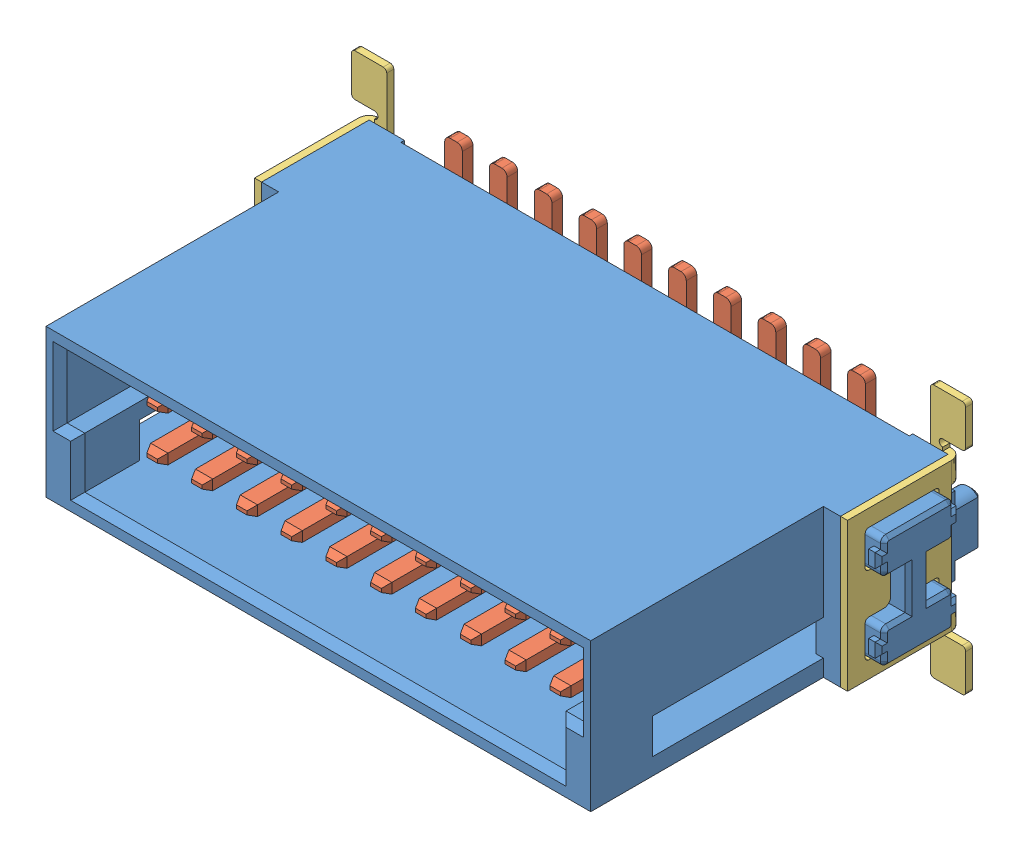
SolidWorks assembly m55-7022042_asm, configuration Default. Lengths in mm.
Overall size (17.78 7.2 10.6).
24 component instances, 3 part files, 0 mates.
Components (placement in the parent):
- m55-7022042_asm.stp-1: m55-7022042_asm.stp [Default] at origin size (17.78 7.2 10.6)
  - M55-70220_MOULD.stp-1: M55-70220_MOULD.stp [Default] at origin size (17.78 4.2 10.6)
  - M55-702_CONTACT.stp-1: M55-702_CONTACT.stp [Default] at (-5.715 -0.785 8.85) x (1 0 0) z (0 1 0) size (1.1 8.85 2.42)
  - M55-702_CONTACT.stp-2: M55-702_CONTACT.stp [Default] at (-4.445 -0.785 8.85) x (1 0 0) z (0 1 0) size (1.1 8.85 2.42)
  - M55-702_CONTACT.stp-3: M55-702_CONTACT.stp [Default] at (-3.175 -0.785 8.85) x (1 0 0) z (0 1 0) size (1.1 8.85 2.42)
  - M55-702_CONTACT.stp-4: M55-702_CONTACT.stp [Default] at (-1.905 -0.785 8.85) x (1 0 0) z (0 1 0) size (1.1 8.85 2.42)
  - M55-702_CONTACT.stp-5: M55-702_CONTACT.stp [Default] at (-0.635 -0.785 8.85) x (1 0 0) z (0 1 0) size (1.1 8.85 2.42)
  - M55-702_CONTACT.stp-6: M55-702_CONTACT.stp [Default] at (0.635 -0.785 8.85) x (1 0 0) z (0 1 0) size (1.1 8.85 2.42)
  - M55-702_CONTACT.stp-7: M55-702_CONTACT.stp [Default] at (1.905 -0.785 8.85) x (1 0 0) z (0 1 0) size (1.1 8.85 2.42)
  - M55-702_CONTACT.stp-8: M55-702_CONTACT.stp [Default] at (3.175 -0.785 8.85) x (1 0 0) z (0 1 0) size (1.1 8.85 2.42)
  - M55-702_CONTACT.stp-9: M55-702_CONTACT.stp [Default] at (4.445 -0.785 8.85) x (1 0 0) z (0 1 0) size (1.1 8.85 2.42)
  - M55-702_CONTACT.stp-10: M55-702_CONTACT.stp [Default] at (5.715 -0.785 8.85) x (1 0 0) z (0 1 0) size (1.1 8.85 2.42)
  - M55-702_CONTACT.stp-11: M55-702_CONTACT.stp [Default] at (-5.715 0.785 8.85) x (-1 0 0) z (0 -1 0) size (1.1 8.85 2.42)
  - M55-702_CONTACT.stp-12: M55-702_CONTACT.stp [Default] at (-4.445 0.785 8.85) x (-1 0 0) z (0 -1 0) size (1.1 8.85 2.42)
  - M55-702_CONTACT.stp-13: M55-702_CONTACT.stp [Default] at (-3.175 0.785 8.85) x (-1 0 0) z (0 -1 0) size (1.1 8.85 2.42)
  - M55-702_CONTACT.stp-14: M55-702_CONTACT.stp [Default] at (-1.905 0.785 8.85) x (-1 0 0) z (0 -1 0) size (1.1 8.85 2.42)
  - M55-702_CONTACT.stp-15: M55-702_CONTACT.stp [Default] at (-0.635 0.785 8.85) x (-1 0 0) z (0 -1 0) size (1.1 8.85 2.42)
  - M55-702_CONTACT.stp-16: M55-702_CONTACT.stp [Default] at (0.635 0.785 8.85) x (-1 0 0) z (0 -1 0) size (1.1 8.85 2.42)
  - M55-702_CONTACT.stp-17: M55-702_CONTACT.stp [Default] at (1.905 0.785 8.85) x (-1 0 0) z (0 -1 0) size (1.1 8.85 2.42)
  - M55-702_CONTACT.stp-18: M55-702_CONTACT.stp [Default] at (3.175 0.785 8.85) x (-1 0 0) z (0 -1 0) size (1.1 8.85 2.42)
  - M55-702_CONTACT.stp-19: M55-702_CONTACT.stp [Default] at (4.445 0.785 8.85) x (-1 0 0) z (0 -1 0) size (1.1 8.85 2.42)
  - M55-702_CONTACT.stp-20: M55-702_CONTACT.stp [Default] at (5.715 0.785 8.85) x (-1 0 0) z (0 -1 0) size (1.1 8.85 2.42)
  - M55-700_STRAP.stp-1: M55-700_STRAP.stp [Default] at (-8.21 0 0) x (1 0 0) z (0 -1 0) size (1 3.25 7.2)
  - M55-700_STRAP.stp-2: M55-700_STRAP.stp [Default] at (8.21 0 0) x (-1 0 0) z (0 1 0) size (1 3.25 7.2)
